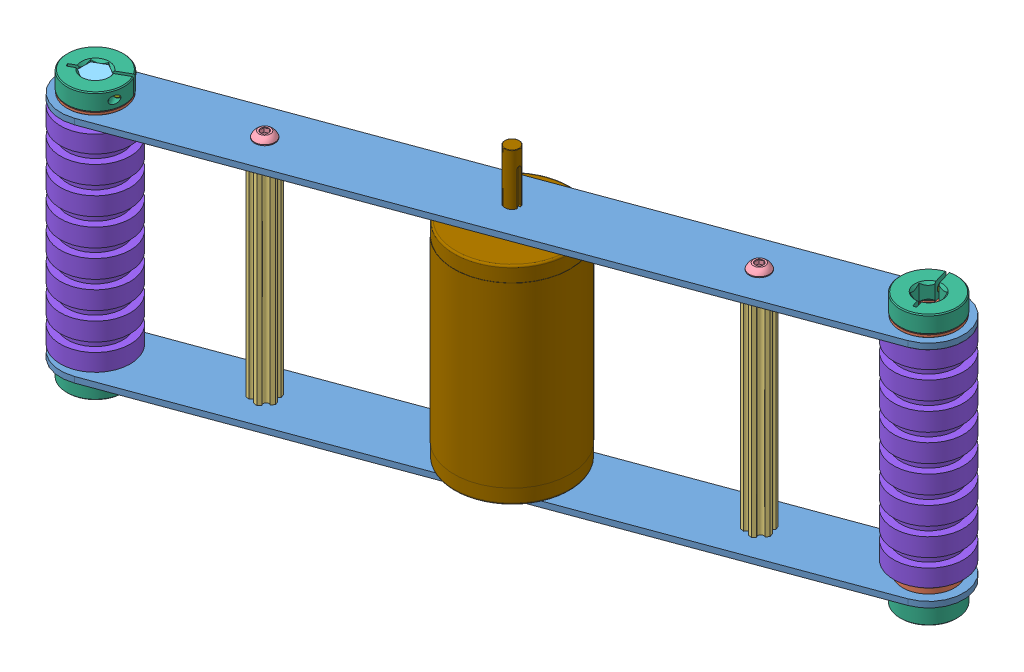
SolidWorks assembly Arm_Assembly, configuration Default. Lengths in mm.
Overall size (386.7 166.48 173.84).
29 component instances, 9 part files, 0 mates.
Components (placement in the parent):
- Assem1^Arm_Assembly-1: Assem1^Arm_Assembly [Default] at (-12.9301 17.282 -5.8762) size (386.7 166.48 173.84) (virtual)
  - Arms_Top_Bottom_Plate-1: Arms_Top_Bottom_Plate [Default] at (-277.9606 169.7769 222.1703) x (-0.345233 0 -0.938517) z (0 -1 0) size (38.57 397.35 3.17)
  - 1_2_Hex_Bore_Flange_Bearing-1: 1_2_Hex_Bore_Flange_Bearing [Default] at (58.7558 163.3736 98.3094) x (0.284409 0 0.958703) z (0 1 0) size (31.12 31.12 7.93)
  - 1_2_Hex_Bore_Flange_Bearing-2: 1_2_Hex_Bore_Flange_Bearing [Default] at (-277.9606 163.3736 222.1703) x (-0.84433 0 -0.535824) z (0 1 0) size (31.12 31.12 7.93)
  - 1_2_Hex_Bore_Flange_Bearing-3: 1_2_Hex_Bore_Flange_Bearing [Default] at (-277.9606 49.4043 222.1703) x (0.84433 0 0.535824) z (0 -1 0) size (31.12 31.12 7.93)
  - 1_2_Hex_Bore_Flange_Bearing-4: 1_2_Hex_Bore_Flange_Bearing [Default] at (58.7558 49.4043 98.3094) x (-0.284409 0 -0.958703) z (0 -1 0) size (31.12 31.12 7.93)
  - Arms_Top_Bottom_Plate-2: Arms_Top_Bottom_Plate [Default] at (-277.9606 43.0009 222.1703) x (0.345233 0 0.938517) z (0 1 0) size (38.57 397.35 3.17)
  - 1_2_5__Churro_Tube-1: 1_2_5__Churro_Tube [Default] at (-209.5369 98.8759 197.0007) x (-0.345233 0 -0.938517) z (0 1 0) size (14.66 12.7 120.43)
  - 1_2_5__Churro_Tube-2: 1_2_5__Churro_Tube [Default] at (-9.6679 98.8759 123.479) x (-0.345233 0 -0.938517) z (0 1 0) size (14.66 12.7 120.43)
  - 1_4-20_1_2_Button_Cap-1: 1_4-20_1_2_Button_Cap [Default] at (-9.6679 173.1297 123.479) x (-0.345233 0 -0.938517) z (0 1 0) size (11.17 11.22 17.01)
  - 1_4-20_1_2_Button_Cap-2: 1_4-20_1_2_Button_Cap [Default] at (-209.5369 173.1297 197.0007) x (-0.345233 0 -0.938517) z (0 1 0) size (11.17 11.22 17.01)
  - 1_4-20_1_2_Button_Cap-3: 1_4-20_1_2_Button_Cap [Default] at (-9.6679 39.6481 123.479) x (-0.345233 0 -0.938517) z (0 -1 0) size (11.17 11.22 17.01)
  - 1_4-20_1_2_Button_Cap-4: 1_4-20_1_2_Button_Cap [Default] at (-209.5369 39.6481 197.0007) x (-0.345233 0 -0.938517) z (0 -1 0) size (11.17 11.22 17.01)
  - 0.5_Hex_Shaft_Idle-1: 0.5_Hex_Shaft_Idle [Default] at (-271.2056 40.7057 219.3585) x (-0.384298 0 -0.923209) z (0.923209 0 -0.384298) size (13.49 146 14.63)
  - 1_2_Hex_Shaft_Collar-1: 1_2_Hex_Shaft_Collar [Default] at (127.7816 408.0678 12.6986) size (42.94 10.19 42.95)
    - am-1238 Clamp Only-1: am-1238 Clamp Only [Default] at (-405.7309 -236.7669 209.4653) x (0.868523 0 -0.495649) z (0.495649 0 0.868523) size (31.47 10.19 31.5)
    - am-1238 Screw Only_91251A194-1: am-1238 Screw Only_91251A194 [Default] at (-392.5372 -232.0044 210.8557) x (0.868523 0 -0.495649) z (0.495649 0 0.868523) size (6.86 6.86 17.11)
  - 1_2_Hex_Shaft_Collar_1-1: 1_2_Hex_Shaft_Collar_1 [Default] at (75.9024 412.9384 -146.8237) size (32.06 10.19 32.03)
    - am-1238 Clamp Only-1: am-1238 Clamp Only [Default] at (-353.863 -379.4625 368.9941) x (0.017972 0 -0.999838) z (0.999838 0 0.017972) size (31.47 10.19 31.5)
    - am-1238 Screw Only_91251A194-1: am-1238 Screw Only_91251A194 [Default] at (-345.9237 -374.7 358.3651) x (0.017972 0 -0.999838) z (0.999838 0 0.017972) size (6.86 6.86 17.11)
  - Belt_Hub-1: Belt_Hub [Default] at (-277.9606 48.8891 222.1703) x (-0.384298 0 -0.923209) z (0 1 0) size (38.57 38.57 113.97)
  - Belt_Hub-2: Belt_Hub [Default] at (58.7558 52.1174 98.3094) x (-0.316916 0 0.948454) z (0 1 0) size (38.57 38.57 113.97)
  - 1_2_Hex_Shaft_Collar_2-1: 1_2_Hex_Shaft_Collar_2 [Default] at (-0.3501 536.1995 139.4112) size (39.15 10.19 39.13)
    - am-1238 Clamp Only-1: am-1238 Clamp Only [Default] at (59.1023 -364.8986 -41.1142) x (-0.284409 0 -0.958703) z (0.958703 0 -0.284409) size (31.47 10.19 31.5)
    - am-1238 Screw Only_91251A194-1: am-1238 Screw Only_91251A194 [Default] at (63.4663 -360.1361 -53.6427) x (-0.284409 0 -0.958703) z (0.958703 0 -0.284409) size (6.86 6.86 17.11)
  - 1_2_Hex_Shaft_Collar_3-1: 1_2_Hex_Shaft_Collar_3 [Default] at (56.7879 209.4764 105.0462) size (39.15 10.19 39.13)
    - am-1238 Clamp Only-1: am-1238 Clamp Only [Default] at (1.968 -177.5245 -6.7368) x (-0.284409 0 -0.958703) z (0.958703 0 -0.284409) size (31.47 10.19 31.5)
    - am-1238 Screw Only_91251A194-1: am-1238 Screw Only_91251A194 [Default] at (6.332 -172.762 -19.2653) x (-0.284409 0 -0.958703) z (0.958703 0 -0.284409) size (6.86 6.86 17.11)
  - 2.5in CIM-1: 2.5in CIM [Default] at (-145.1624 143.4879 269.5361) x (1 0 0) z (0 1 0) size (64.01 64.01 154.94)
